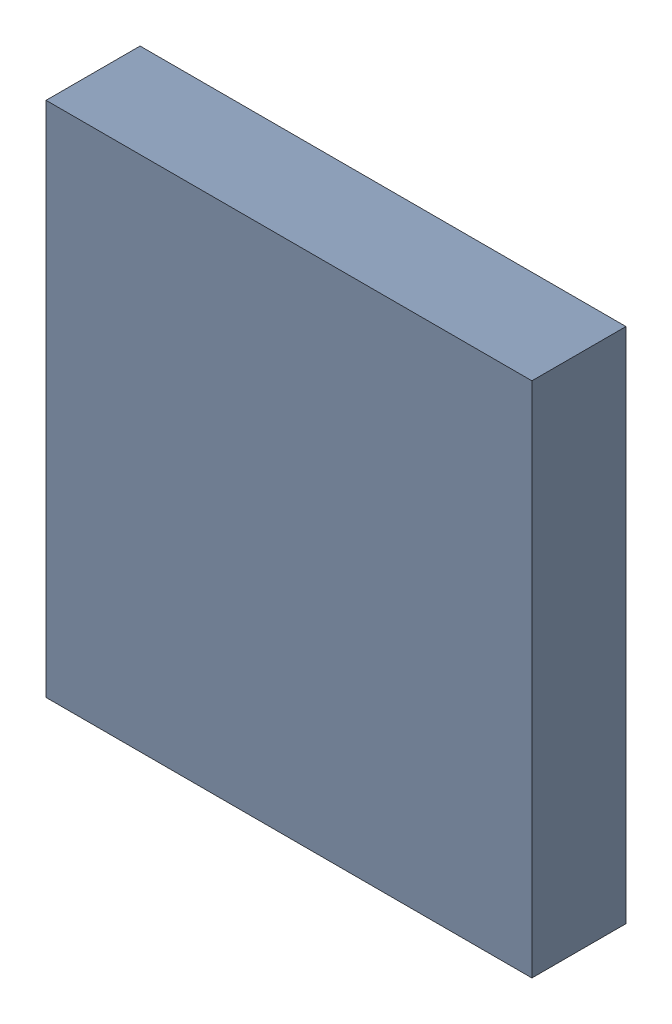
SolidWorks assembly U200_1v2(2)^MTi-1-SoB_v2, configuration Default. Lengths in mm.
Overall size (3.1 3.3 0.6).
2 component instances, 1 part files, 0 mates.
Components (placement in the parent):
- 7460079024(2)^U200_1v2(2)_MTi-1-SoB_v2-1: 7460079024(2)^U200_1v2(2)_MTi-1-SoB_v2 [Default] at (5.6 3.4 0) size (3.1 3.3 0.6)
  - Extruded(2)^7460079024(2)_U200_1v2(2)_MTi-1-SoB_v2-1: Extruded(2)^7460079024(2)_U200_1v2(2)_MTi-1-SoB_v2 [Default] at origin size (3.1 3.3 0.6)
